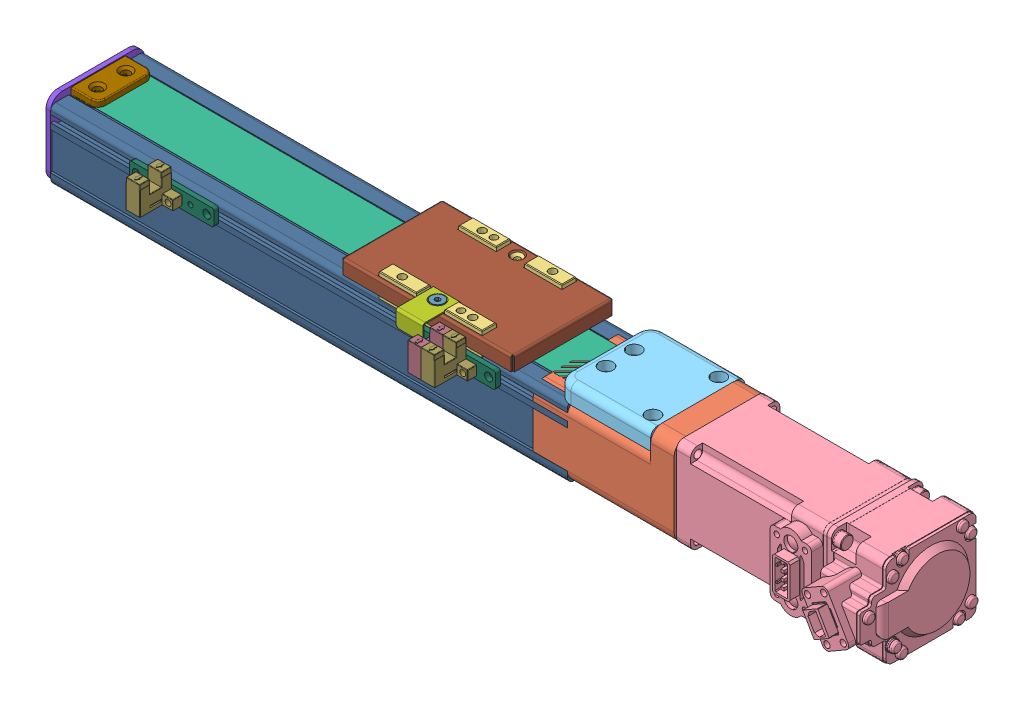
SolidWorks assembly S4M-BC-100W, configuration 默认. Lengths in mm.
Overall size (360 39 59.1).
18 component instances, 15 part files, 36 mates.
Components (placement in the parent):
- 40F导轨MRU9W^S4M-BC-100W-1: 40F导轨MRU9W^S4M-BC-100W [預設] at (0.7794 65.5829 -10.4204) size (220 7.3 18) (virtual)
-  电机板40F^S4M-BC-100W-1:  电机板40F^S4M-BC-100W [默认] at (-14.2206 66.0829 -30.4204) x (0 0 1) z (0 1 0) size (40 60 38) (virtual)
- 滑台40F^S4M-BC-100W-1: 滑台40F^S4M-BC-100W [默认] at (-79.9706 94.5829 9.5796) x (0 0 -1) z (1 0 0) size (40 10 44) (virtual)
- MSME012G1U_1__2_03^S4M-BC-100W-1: MSME012G1U_1__2_03^S4M-BC-100W [默认] at (42.7794 85.0829 -10.4204) x (-1 0 0) z (0 1 0) size (117.5 57.1 39) (virtual)
- 压板40F^S4M-BC-100W-1: 压板40F^S4M-BC-100W [默认] at (14.7794 102.3329 -22.9204) x (-1 0 0) z (0 0 -1) size (40 7.9 40) (virtual)
- 钢带40F^S4M-BC-100W-1: 钢带40F^S4M-BC-100W [第一实例] at (-218.7206 96.0829 -10.4204) x (0 0 -1) z (1 0 0) size (23.5 0.1 235) (virtual)
- 感应片40F^S4M-BC-100W-1: 感应片40F^S4M-BC-100W [默认] at (-52.2206 103.5829 2.5796) x (0 0 1) z (-1 0 0) size (16 7 11.5) (virtual)
- 轴承板40F^S4M-BC-100W-1: 轴承板40F^S4M-BC-100W [默认] at (-207.7206 66.0829 -30.4204) x (-1 0 0) z (0 1 0) size (2 40 32.6) (virtual)
- 压片40F^S4M-BC-100W-1: 压片40F^S4M-BC-100W [Default] at (-219.7206 96.4329 -14.6704) x (0 0 -1) z (1 0 0) size (23.5 3 12) (virtual)
- 侧盖CG40F^S4M-BC-100W-1: 侧盖CG40F^S4M-BC-100W [默认] at (0.2794 -1498.1552 -2363.4672) x (0 0 1) z (-1 0 0) size (11 30 220) (virtual)
- 侧盖CG40F^S4M-BC-100W-2: 侧盖CG40F^S4M-BC-100W [默认] at (-219.7206 -1498.1552 2342.6264) x (0 0 -1) z (1 0 0) size (11 30 220) (virtual)
-  导向盖DX40F^S4M-BC-100W-1:  导向盖DX40F^S4M-BC-100W [默认] at (-57.9706 102.5829 -10.4204) x (-1 0 0) z (0 0 1) size (73 6 43) (virtual)
- 光电开关FC-SPX203^S4M-BC-100W-1: 光电开关FC-SPX203^S4M-BC-100W [默认] at (-43.7206 88.9829 18.3296) x (0 0 1) z (0 1 0) size (15 10.5 12.2) (virtual)
-  光电开关FC-SPX202^S4M-BC-100W-2:  光电开关FC-SPX202^S4M-BC-100W [默认] at (-49.2206 88.9829 18.3296) x (0 0 -1) z (0 1 0) size (15 10.5 12.2) (virtual)
- hexagon socket countersunk head screws gb-1: hexagon socket countersunk head screws gb [GB_FASTENER_SCREWS_HSCHS M3X8-N] at (-57.9706 103.6929 6.5796) x (0 -1 0) z (-0.546944 0 0.837169) size (8 5.54 5.54)
- 开关座KZ65F^S4M-BC-100W-1: 开关座KZ65F^S4M-BC-100W [默认] at (-184.2206 94.4829 11.5796) x (1 0 0) z (0 -1 0) size (36 2 7) (virtual)
- 开关座KZ65F^S4M-BC-100W-2: 开关座KZ65F^S4M-BC-100W [默认] at (-64.2206 94.4829 11.5796) x (1 0 0) z (0 -1 0) size (36 2 7) (virtual)
- 光电开关FC-SPX203^S4M-BC-100W-2: 光电开关FC-SPX203^S4M-BC-100W [默认] at (-169.2206 88.9829 18.3296) x (0 0 1) z (0 1 0) size (15 10.5 12.2) (virtual)
Mates (geometry in assembly coordinates):
- 重合836: coincident: plane of 侧盖CG40F^S4M-BC-100W-1 through (-219.7206 95.9829 -28.4204) normal (0 1 0); plane of 侧盖CG40F^S4M-BC-100W-2 through (0.2794 95.9829 7.5796) normal (0 1 0)
- 重合899: coincident: plane of 侧盖CG40F^S4M-BC-100W-2 through (0.2794 89.4329 9.5796) normal (0 0 1); plane of 开关座KZ65F^S4M-BC-100W-1 through (-184.2206 87.4829 9.5796) normal (0 0 -1)
- 宽度3: width: plane of 侧盖CG40F^S4M-BC-100W-2 through (0.2794 89.4329 9.5796) normal (0 1 0); plane of 侧盖CG40F^S4M-BC-100W-2 through (0.2794 92.5329 9.5796) normal (0 -1 0); plane of 开关座KZ65F^S4M-BC-100W-1 through (-184.2206 94.4829 11.5796) normal (0 1 0); plane of 开关座KZ65F^S4M-BC-100W-1 through (-184.2206 87.4829 11.5796) normal (0 -1 0)
- 重合901: coincident: plane of 开关座KZ65F^S4M-BC-100W-1 through (-184.2206 87.4829 11.5796) normal (0 0 1); plane of 开关座KZ65F^S4M-BC-100W-2 through (-64.2206 87.4829 11.5796) normal (0 0 1)
- 重合902: coincident: plane of 开关座KZ65F^S4M-BC-100W-1 through (-184.2206 94.4829 11.5796) normal (0 1 0); plane of 开关座KZ65F^S4M-BC-100W-2 through (-64.2206 94.4829 11.5796) normal (0 1 0)
- 重合906: coincident: plane of  电机板40F^S4M-BC-100W-1 through (45.7794 104.0829 9.5796) normal (0 0 1); plane of 侧盖CG40F^S4M-BC-100W-2 through (0.2794 89.4329 9.5796) normal (0 0 1)
- 重合907: coincident: plane of  电机板40F^S4M-BC-100W-1 through (-14.2206 104.0829 -30.4204) normal (0 0 -1); plane of 侧盖CG40F^S4M-BC-100W-1 through (-219.7206 89.4329 -30.4204) normal (0 0 -1)
- 重合911: coincident: plane of 侧盖CG40F^S4M-BC-100W-1 through (0.2794 68.9829 -27.4204) normal (1 0 0); plane of 侧盖CG40F^S4M-BC-100W-2 through (0.2794 68.9829 6.5796) normal (1 0 0)
- 距离16: distance = 45.5 mm: plane of 侧盖CG40F^S4M-BC-100W-1 through (0.2794 68.9829 -27.4204) normal (1 0 0); plane of MSME012G1U_1__2_03^S4M-BC-100W-1 through (45.7794 85.0829 -10.4204) normal (-1 0 0)
- 距离17: distance = 0.5 mm: plane of 40F导轨MRU9W^S4M-BC-100W-1 through (-219.2206 65.5829 -18.8204) normal (0 -1 0); plane of 轴承板40F^S4M-BC-100W-1 through (-207.7206 66.0829 -30.4204) normal (0 -1 0)
- 距离18: distance = 2.5 mm: plane of 轴承板40F^S4M-BC-100W-1 through (-221.7206 98.6829 -30.4204) normal (-1 0 0); plane of 40F导轨MRU9W^S4M-BC-100W-1 through (-219.2206 65.5829 -1.4204) normal (-1 0 0)
- 重合915: coincident: plane of 轴承板40F^S4M-BC-100W-1 through (-207.7206 98.6829 9.5796) normal (0 0 1); plane of 侧盖CG40F^S4M-BC-100W-2 through (0.2794 70.9829 9.5796) normal (0 0 1)
- 距离19: distance = 14 mm: plane of 压片40F^S4M-BC-100W-1 through (-207.7206 98.6829 -22.1704) normal (1 0 0); plane of 轴承板40F^S4M-BC-100W-1 through (-221.7206 98.6829 -30.4204) normal (-1 0 0)
- 距离20: distance = 8.25 mm: plane of 压片40F^S4M-BC-100W-1 through (-207.7206 98.6829 1.3296) normal (0 0 1); plane of 轴承板40F^S4M-BC-100W-1 through (-207.7206 98.6829 9.5796) normal (0 0 1)
- 重合918: coincident: plane of 轴承板40F^S4M-BC-100W-1 through (-207.7206 98.6829 -30.4204) normal (0 1 0); plane of 压片40F^S4M-BC-100W-1 through (-219.7206 98.6829 -14.6704) normal (0 1 0)
- 距离21: distance = 2.5 mm: plane of 钢带40F^S4M-BC-100W-1 through (-218.7206 96.1829 -10.4204) normal (0 1 0); plane of 压片40F^S4M-BC-100W-1 through (-219.7206 98.6829 -14.6704) normal (0 1 0)
- 重合920: coincident: plane of 钢带40F^S4M-BC-100W-1 through (16.2794 96.1829 1.3296) normal (0 0 1); plane of 压片40F^S4M-BC-100W-1 through (-207.7206 98.6829 1.3296) normal (0 0 1)
- 距离22: distance = 1 mm: plane of 轴承板40F^S4M-BC-100W-1 through (-219.7206 66.0829 -30.4204) normal (1 0 0); plane of 钢带40F^S4M-BC-100W-1 through (-218.7206 96.1829 1.3296) normal (-1 0 0)
- 距离23: distance = 1.5 mm: plane of 滑台40F^S4M-BC-100W-1 through (-35.9706 104.5829 9.5796) normal (0 1 0); plane of  导向盖DX40F^S4M-BC-100W-1 through (-57.9706 103.0829 -10.4204) normal (0 1 0)
- 距离24: distance = 14.5 mm: plane of 滑台40F^S4M-BC-100W-1 through (-79.9706 94.5829 9.5796) normal (-1 0 0); plane of  导向盖DX40F^S4M-BC-100W-1 through (-94.4706 102.5829 -10.4204) normal (-1 0 0)
- 距离25: distance = 1.5 mm: plane of 滑台40F^S4M-BC-100W-1 through (-35.9706 94.5829 -30.4204) normal (0 0 -1); plane of  导向盖DX40F^S4M-BC-100W-1 through (-57.9706 102.5829 -31.9204) normal (0 0 -1)
- 距离26: distance = 0.6 mm: plane of 压板40F^S4M-BC-100W-1 through (14.7794 103.9829 -22.9204) normal (0 1 0); plane of 滑台40F^S4M-BC-100W-1 through (-35.9706 104.5829 9.5796) normal (0 1 0)
- 距离27: distance = 0 mm: plane of  电机板40F^S4M-BC-100W-1 through (45.7794 104.0829 9.5796) normal (0 0 1); plane of 滑台40F^S4M-BC-100W-1 through (-35.9706 94.5829 9.5796) normal (0 0 1)
- 重合921: coincident: plane of 感应片40F^S4M-BC-100W-1 through (-63.7206 103.0829 2.5796) normal (0 -1 0); plane of  导向盖DX40F^S4M-BC-100W-1 through (-57.9706 103.0829 -10.4204) normal (0 1 0)
- 同心857: concentric: cone of 滑台40F^S4M-BC-100W-1 through (-57.9706 101.5829 6.5796) axis (0 -1 0); cone of 感应片40F^S4M-BC-100W-1 through (-57.9706 103.5829 6.5796) axis (0 -1 0)
- 平行1: parallel: plane of 感应片40F^S4M-BC-100W-1 through (-63.7206 103.5829 18.5796) normal (0 0 1); plane of  导向盖DX40F^S4M-BC-100W-1 through (-57.9706 102.5829 11.0796) normal (0 0 1)
- 距离28: distance = 37.5 mm: plane of 轴承板40F^S4M-BC-100W-1 through (-221.7206 98.6829 -30.4204) normal (-1 0 0); plane of 开关座KZ65F^S4M-BC-100W-1 through (-184.2206 87.4829 9.5796) normal (-1 0 0)
- 重合925: coincident: plane of 光电开关FC-SPX203^S4M-BC-100W-1 through (-40.9126 100.9829 24.9566) normal (0 1 0); plane of  光电开关FC-SPX202^S4M-BC-100W-2 through (-52.0286 100.9829 11.7026) normal (0 1 0)
- 重合926: coincident: plane of  光电开关FC-SPX202^S4M-BC-100W-2 through (-56.7226 101.0189 11.5796) normal (0 0 -1); plane of 开关座KZ65F^S4M-BC-100W-2 through (-64.2206 87.4829 11.5796) normal (0 0 1)
- 同心859: concentric: cylinder of  光电开关FC-SPX202^S4M-BC-100W-2 through (-54.7206 90.9829 15.5796) axis (0 0 -1) radius 1.25; cylinder of 开关座KZ65F^S4M-BC-100W-2 through (-54.7206 90.9829 11.5796) axis (0 0 1) radius 1.05
- 重合927: coincident: plane of  光电开关FC-SPX202^S4M-BC-100W-2 through (-52.0286 100.9829 20.9526) normal (0 1 0); plane of 光电开关FC-SPX203^S4M-BC-100W-2 through (-166.4126 100.9829 24.9566) normal (0 1 0)
- 重合928: coincident: plane of 开关座KZ65F^S4M-BC-100W-1 through (-184.2206 87.4829 11.5796) normal (0 0 1); plane of 光电开关FC-SPX203^S4M-BC-100W-2 through (-172.2226 101.0189 11.5796) normal (0 0 -1)
- 同心860: concentric: cylinder of 光电开关FC-SPX203^S4M-BC-100W-2 through (-163.7206 90.9829 11.5796) axis (0 0 1) radius 1.25; cylinder of 开关座KZ65F^S4M-BC-100W-1 through (-163.7206 90.9829 11.5796) axis (0 0 1) radius 1.05
- 重合930: coincident: plane of 感应片40F^S4M-BC-100W-1 through (-52.2206 102.5829 17.5796) normal (1 0 0); plane of  光电开关FC-SPX202^S4M-BC-100W-2 through (-52.2206 99.1829 25.1416) normal (-1 0 0)
- 同心861: concentric: cone of 滑台40F^S4M-BC-100W-1 through (-57.9706 101.5829 6.5796) axis (0 -1 0); cone of hexagon socket countersunk head screws gb-1 through (-57.9706 101.8329 6.5796) axis (0 -1 0)
- 重合931: coincident: cone of 滑台40F^S4M-BC-100W-1 through (-57.9706 101.5829 6.5796) axis (0 -1 0); cone of hexagon socket countersunk head screws gb-1 through (-57.9706 101.8329 6.5796) axis (0 -1 0)
